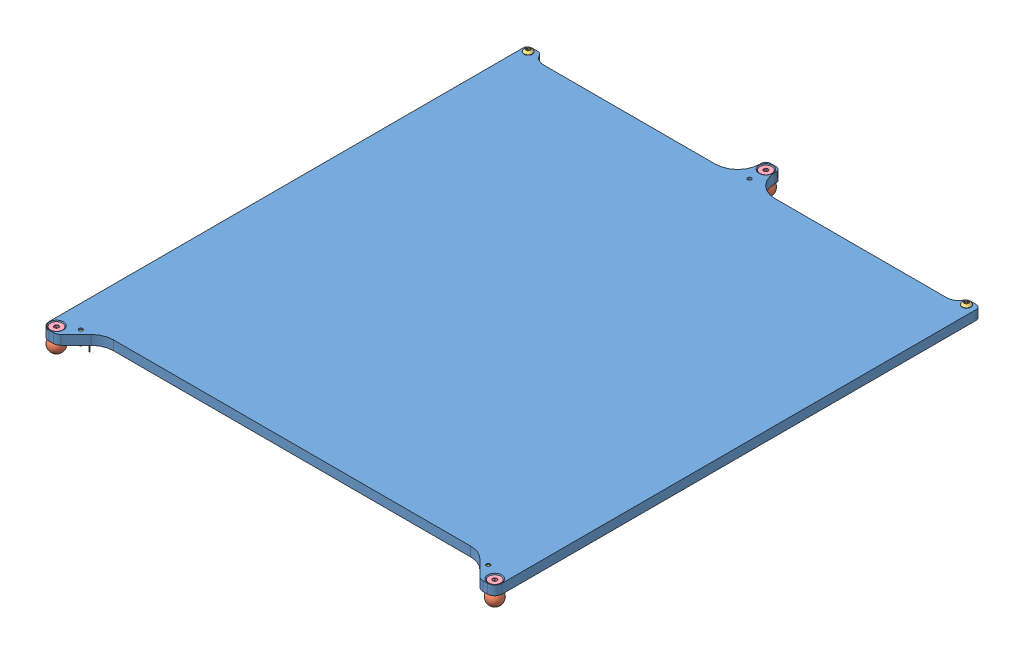
SolidWorks assembly build_plate_assembly, configuration Default. Lengths in mm.
Overall size (307.74 18.38 342.58).
16 component instances, 6 part files, 0 mates.
Components (placement in the parent):
- z_plate_3-1: z_plate_3 [Default] at (139.571 125.073 235.8874) size (305 6.35 340)
- m4_threaded_ball-1: m4_threaded_ball [Default] at (139.571 116.073 69.3874) x (0.989184 0 0.146678) z (-0.146678 0 0.989184) size (10 10 10)
- m4_threaded_ball-2: m4_threaded_ball [Default] at (287.071 116.073 399.3874) x (-0.982488 0 -0.186325) z (0.186325 0 -0.982488) size (10 10 10)
- m4_threaded_ball-3: m4_threaded_ball [Default] at (-7.929 116.073 399.3874) x (-0.844742 0 0.535173) z (-0.535173 0 -0.844742) size (10 10 10)
- m3_6mm_buttonhead_screw_92095A179_92095A179-1: m3_6mm_buttonhead_screw_92095A179_92095A179 [Default] at (-7.929 134.073 81.8874) x (0.52561 0 -0.850725) z (0 1 0) size (5.74 5.77 8.05)
- m3_6mm_buttonhead_screw_92095A179_92095A179-2: m3_6mm_buttonhead_screw_92095A179_92095A179 [Default] at (287.071 134.073 81.8874) x (0.732583 0 0.680678) z (0 1 0) size (5.74 5.77 8.05)
- m4_10mm_flathead_screw_92125A190_92125A190-1: m4_10mm_flathead_screw_92125A190_92125A190 [Default] at (-7.929 131.023 399.3874) x (0.606592 0 -0.795013) z (0 1 0) size (8 8 10.19)
- m4_10mm_flathead_screw_92125A190_92125A190-2: m4_10mm_flathead_screw_92125A190_92125A190 [Default] at (287.071 131.023 399.3874) x (0.707729 0 -0.706484) z (0 1 0) size (8 8 10.19)
- m4_10mm_flathead_screw_92125A190_92125A190-3: m4_10mm_flathead_screw_92125A190_92125A190 [Default] at (139.571 131.023 69.3874) x (0.927954 0 -0.372694) z (0 1 0) size (8 8 10.19)
- 7328_solder_terminal_lug_Bent M3 Solder Terminal Lug-1: 7328_solder_terminal_lug_Bent M3 Solder Terminal Lug [Default] at (2.4633 124.693 393.3874) x (0.707107 0 0.707107) z (0.707107 0 -0.707107) size (7.2 6.35 7.92)
- 7328_solder_terminal_lug_Bent M3 Solder Terminal Lug-2: 7328_solder_terminal_lug_Bent M3 Solder Terminal Lug [Default] at (276.6787 124.693 393.3874) x (0.707107 0 -0.707107) z (-0.707107 0 -0.707107) size (7.2 6.35 7.92)
- 7328_solder_terminal_lug_Bent M3 Solder Terminal Lug-3: 7328_solder_terminal_lug_Bent M3 Solder Terminal Lug [Default] at (139.571 123.931 80.3874) x (-1 0 0) z (0 0 1) size (7.2 6.35 7.92)
- thermistor_mockup_NTCALUG01A103F-1: thermistor_mockup_NTCALUG01A103F [Default] at (139.571 124.692 80.3874) x (0 0 1) z (1 0 0) size (9.16 4.12 15.29)
- m3_6mm_buttonhead_screw_92095A179_92095A179-3: m3_6mm_buttonhead_screw_92095A179_92095A179 [Default] at (139.571 122.281 80.3874) x (0.664384 0 -0.747391) z (0 -1 0) size (5.74 5.77 8.05)
- m3_6mm_buttonhead_screw_92095A179_92095A179-4: m3_6mm_buttonhead_screw_92095A179_92095A179 [Default] at (2.4633 123.043 393.3874) x (1 0 0) z (0 -1 0) size (5.74 5.77 8.05)
- m3_6mm_buttonhead_screw_92095A179_92095A179-5: m3_6mm_buttonhead_screw_92095A179_92095A179 [Default] at (276.6787 123.043 393.3874) x (1 0 0) z (0 -1 0) size (5.74 5.77 8.05)
